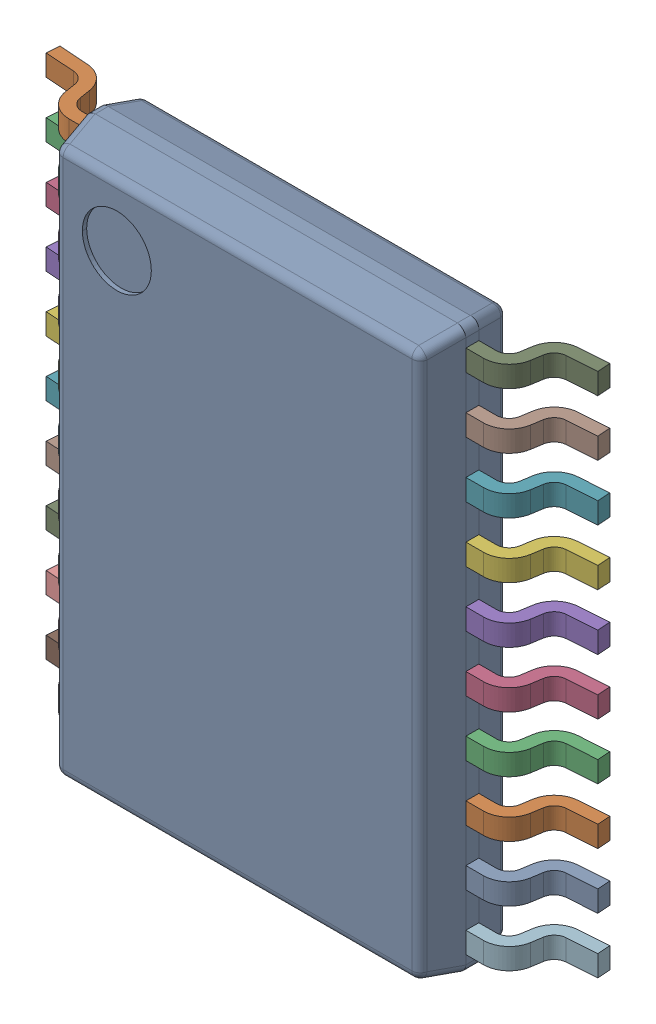
SolidWorks assembly IC14_1.step, configuration Default. Lengths in mm.
Overall size (6.4 6.5 1.13).
22 component instances, 2 part files, 0 mates.
Components (placement in the parent):
- 9651432272_1.step-11: 9651432272_1.step [Default] at (484.632 272.258 0) size (6.4 6.5 1.13)
  - BODY-TSSOP_1.step-11: BODY-TSSOP_1.step [Default] at (0 0 0.68) x (1 0 0) z (0 -1 0) size (4.4 1 6.5)
  - LEAD-TSSOP_1.step-242: LEAD-TSSOP_1.step [Default] at (-2.575 2.925 0.25) x (0 -1 0) z (-1 0 0) size (0.24 0.68 1)
  - LEAD-TSSOP_1.step-243: LEAD-TSSOP_1.step [Default] at (-2.575 2.275 0.25) x (0 -1 0) z (-1 0 0) size (0.24 0.68 1)
  - LEAD-TSSOP_1.step-244: LEAD-TSSOP_1.step [Default] at (-2.575 1.625 0.25) x (0 -1 0) z (-1 0 0) size (0.24 0.68 1)
  - LEAD-TSSOP_1.step-245: LEAD-TSSOP_1.step [Default] at (-2.575 0.975 0.25) x (0 -1 0) z (-1 0 0) size (0.24 0.68 1)
  - LEAD-TSSOP_1.step-246: LEAD-TSSOP_1.step [Default] at (-2.575 0.325 0.25) x (0 -1 0) z (-1 0 0) size (0.24 0.68 1)
  - LEAD-TSSOP_1.step-247: LEAD-TSSOP_1.step [Default] at (-2.575 -0.325 0.25) x (0 -1 0) z (-1 0 0) size (0.24 0.68 1)
  - LEAD-TSSOP_1.step-248: LEAD-TSSOP_1.step [Default] at (-2.575 -0.975 0.25) x (0 -1 0) z (-1 0 0) size (0.24 0.68 1)
  - LEAD-TSSOP_1.step-249: LEAD-TSSOP_1.step [Default] at (-2.575 -1.625 0.25) x (0 -1 0) z (-1 0 0) size (0.24 0.68 1)
  - LEAD-TSSOP_1.step-250: LEAD-TSSOP_1.step [Default] at (-2.575 -2.275 0.25) x (0 -1 0) z (-1 0 0) size (0.24 0.68 1)
  - LEAD-TSSOP_1.step-251: LEAD-TSSOP_1.step [Default] at (-2.575 -2.925 0.25) x (0 -1 0) z (-1 0 0) size (0.24 0.68 1)
  - LEAD-TSSOP_1.step-252: LEAD-TSSOP_1.step [Default] at (2.575 -2.925 0.25) x (0 1 0) z (1 0 0) size (0.24 0.68 1)
  - LEAD-TSSOP_1.step-253: LEAD-TSSOP_1.step [Default] at (2.575 -2.275 0.25) x (0 1 0) z (1 0 0) size (0.24 0.68 1)
  - LEAD-TSSOP_1.step-254: LEAD-TSSOP_1.step [Default] at (2.575 -1.625 0.25) x (0 1 0) z (1 0 0) size (0.24 0.68 1)
  - LEAD-TSSOP_1.step-255: LEAD-TSSOP_1.step [Default] at (2.575 -0.975 0.25) x (0 1 0) z (1 0 0) size (0.24 0.68 1)
  - LEAD-TSSOP_1.step-256: LEAD-TSSOP_1.step [Default] at (2.575 -0.325 0.25) x (0 1 0) z (1 0 0) size (0.24 0.68 1)
  - LEAD-TSSOP_1.step-257: LEAD-TSSOP_1.step [Default] at (2.575 0.325 0.25) x (0 1 0) z (1 0 0) size (0.24 0.68 1)
  - LEAD-TSSOP_1.step-258: LEAD-TSSOP_1.step [Default] at (2.575 0.975 0.25) x (0 1 0) z (1 0 0) size (0.24 0.68 1)
  - LEAD-TSSOP_1.step-259: LEAD-TSSOP_1.step [Default] at (2.575 1.625 0.25) x (0 1 0) z (1 0 0) size (0.24 0.68 1)
  - LEAD-TSSOP_1.step-260: LEAD-TSSOP_1.step [Default] at (2.575 2.275 0.25) x (0 1 0) z (1 0 0) size (0.24 0.68 1)
  - LEAD-TSSOP_1.step-261: LEAD-TSSOP_1.step [Default] at (2.575 2.925 0.25) x (0 1 0) z (1 0 0) size (0.24 0.68 1)
